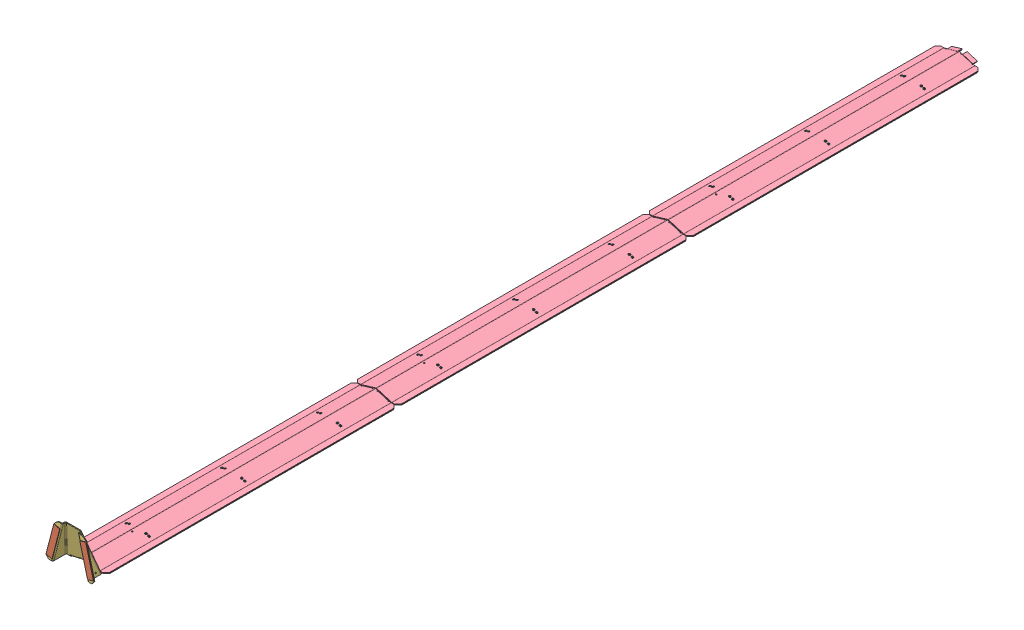
SolidWorks assembly GE-19227, configuration Default. Lengths in mm.
Overall size (196.8 153.5 3680.26).
68 component instances, 7 part files, 9 mates.
Components (placement in the parent):
- GE-19225-1: GE-19225 [Default] at (0 0 58.5238) size (196.8 153.5 83.53)
  - PEM-FH-832-6ZI-1: PEM-FH-832-6ZI [Default] at (71.1866 13.0582 -34.1814) x (-0.967724 -0.252012 0) z (-0.111181 0.426936 -0.897421) size (9.53 6.02 6.02)
  - Hook_1_5-1: Hook_1_5 [Default] at (-97.7586 14.7509 1.5875) x (0.252012 0.967724 0) z (-0.967724 0.252012 0) size (127 1.59 25.4)
  - Hook_1_5-2: Hook_1_5 [Default] at (65.7532 137.6519 1.5875) x (0.252012 -0.967724 0) z (0.967724 0.252012 0) size (127 1.59 25.4)
  - GE-19225-1-1: GE-19225-1 [Default] at origin size (196.8 153.5 81.94)
- GE-19226-1: GE-19226 [Default] at (0 1.5875 -609.5728) size (177.8 23.82 1219.2)
  - GE-19223-1: GE-19223 [Default] at origin size (177.8 22.23 1219.2)
    - GE-19223-1-1: GE-19223-1 [Default] at origin size (177.8 22.23 1219.2)
    - PEM-FH-832-6ZI-1: PEM-FH-832-6ZI [Default] at (7.1934 20.2237 419.1) x (-0.289806 -0.957086 0) z (-0.571052 0.172915 0.802496) size (9.53 6.02 6.02)
  - GE-19224-1: GE-19224 [Default] at (0.0601 3.1126 390.525) x (1 -0.000064 0) z (0 0 1) size (106.54 12.92 31.75)
  - GE-19224-2: GE-19224 [Default] at (0.0601 3.1126 -3.175) x (1 -0.000064 0) z (0 0 1) size (106.54 12.92 31.75)
  - GE-19224-3: GE-19224 [Default] at (0.0601 3.1126 -396.875) x (1 -0.000064 0) z (0 0 1) size (106.54 12.92 31.75)
  - rivet_.1563_.1875-.25-1: rivet_.1563_.1875-.25 [Default] at (47.0652 9.4775 390.525) x (-0.569603 0.172476 -0.80362) z (-0.289806 -0.957086 0) size (8.33 8.33 8.57)
  - rivet_.1563_.1875-.25-2: rivet_.1563_.1875-.25 [Default] at (-47.0652 9.4775 390.525) x (-0.904542 -0.273895 -0.326781) z (0.289806 -0.957086 0) size (8.33 8.33 8.57)
  - rivet_.1563_.1875-.25-3: rivet_.1563_.1875-.25 [Default] at (-34.9102 13.158 -3.175) x (-0.916013 -0.277369 0.289806) z (0.289806 -0.957086 0) size (8.33 8.33 8.57)
  - rivet_.1563_.1875-.25-4: rivet_.1563_.1875-.25 [Default] at (-47.0652 9.4775 -3.175) x (-0.916013 -0.277369 0.289806) z (0.289806 -0.957086 0) size (8.33 8.33 8.57)
  - rivet_.1563_.1875-.25-5: rivet_.1563_.1875-.25 [Default] at (34.9102 13.158 390.525) x (-0.284635 0.086188 0.954754) z (-0.289806 -0.957086 0) size (8.33 8.33 8.57)
  - rivet_.1563_.1875-.25-6: rivet_.1563_.1875-.25 [Default] at (-34.9102 13.158 390.525) x (-0.852981 -0.258283 0.453557) z (0.289806 -0.957086 0) size (8.33 8.33 8.57)
  - rivet_.1563_.1875-.25-7: rivet_.1563_.1875-.25 [Default] at (34.9102 13.158 -3.175) x (-0.728247 0.220513 -0.648868) z (-0.289806 -0.957086 0) size (8.33 8.33 8.57)
  - rivet_.1563_.1875-.25-9: rivet_.1563_.1875-.25 [Default] at (47.0652 9.4775 -3.175) x (-0.856065 0.259217 -0.447167) z (-0.289806 -0.957086 0) size (8.33 8.33 8.57)
  - rivet_.1563_.1875-.25-11: rivet_.1563_.1875-.25 [Default] at (47.0652 9.4775 -396.875) x (-0.934813 0.283061 -0.21448) z (-0.289806 -0.957086 0) size (8.33 8.33 8.57)
  - rivet_.1563_.1875-.25-13: rivet_.1563_.1875-.25 [Default] at (34.9102 13.158 -396.875) x (-0.956866 0.289739 0.021408) z (-0.289806 -0.957086 0) size (8.33 8.33 8.57)
  - rivet_.1563_.1875-.25-15: rivet_.1563_.1875-.25 [Default] at (-34.9102 13.158 -396.875) x (-0.945179 -0.2862 0.157243) z (0.289806 -0.957086 0) size (8.33 8.33 8.57)
  - rivet_.1563_.1875-.25-17: rivet_.1563_.1875-.25 [Default] at (-47.0652 9.4775 -396.875) x (-0.897265 -0.271692 0.347994) z (0.289806 -0.957086 0) size (8.33 8.33 8.57)
  - Hook_1_46-1: Hook_1_46 [Default] at (76.2 -1.5875 10.5486) x (0 0 -1) z (1 0 0) size (1168.4 1.59 25.4)
  - Hook_1_46-2: Hook_1_46 [Default] at (-76.2 -1.5875 10.5486) x (0 0 1) z (-1 0 0) size (1168.4 1.59 25.4)
- GE-19226-2: GE-19226 [Default] at (0 1.5875 -1810.0595) size (177.8 23.82 1219.2)
  - GE-19223-1: GE-19223 [Default] at origin size (177.8 22.23 1219.2)
    - GE-19223-1-1: GE-19223-1 [Default] at origin size (177.8 22.23 1219.2)
    - PEM-FH-832-6ZI-1: PEM-FH-832-6ZI [Default] at (7.1934 20.2237 419.1) x (-0.289806 -0.957086 0) z (-0.571052 0.172915 0.802496) size (9.53 6.02 6.02)
  - GE-19224-1: GE-19224 [Default] at (0.0601 3.1126 390.525) x (1 -0.000064 0) z (0 0 1) size (106.54 12.92 31.75)
  - GE-19224-2: GE-19224 [Default] at (0.0601 3.1126 -3.175) x (1 -0.000064 0) z (0 0 1) size (106.54 12.92 31.75)
  - GE-19224-3: GE-19224 [Default] at (0.0601 3.1126 -396.875) x (1 -0.000064 0) z (0 0 1) size (106.54 12.92 31.75)
  - rivet_.1563_.1875-.25-1: rivet_.1563_.1875-.25 [Default] at (47.0652 9.4775 390.525) x (-0.569603 0.172476 -0.80362) z (-0.289806 -0.957086 0) size (8.33 8.33 8.57)
  - rivet_.1563_.1875-.25-2: rivet_.1563_.1875-.25 [Default] at (-47.0652 9.4775 390.525) x (-0.904542 -0.273895 -0.326781) z (0.289806 -0.957086 0) size (8.33 8.33 8.57)
  - rivet_.1563_.1875-.25-3: rivet_.1563_.1875-.25 [Default] at (-34.9102 13.158 -3.175) x (-0.916013 -0.277369 0.289806) z (0.289806 -0.957086 0) size (8.33 8.33 8.57)
  - rivet_.1563_.1875-.25-4: rivet_.1563_.1875-.25 [Default] at (-47.0652 9.4775 -3.175) x (-0.916013 -0.277369 0.289806) z (0.289806 -0.957086 0) size (8.33 8.33 8.57)
  - rivet_.1563_.1875-.25-5: rivet_.1563_.1875-.25 [Default] at (34.9102 13.158 390.525) x (-0.284635 0.086188 0.954754) z (-0.289806 -0.957086 0) size (8.33 8.33 8.57)
  - rivet_.1563_.1875-.25-6: rivet_.1563_.1875-.25 [Default] at (-34.9102 13.158 390.525) x (-0.852981 -0.258283 0.453557) z (0.289806 -0.957086 0) size (8.33 8.33 8.57)
  - rivet_.1563_.1875-.25-7: rivet_.1563_.1875-.25 [Default] at (34.9102 13.158 -3.175) x (-0.728247 0.220513 -0.648868) z (-0.289806 -0.957086 0) size (8.33 8.33 8.57)
  - rivet_.1563_.1875-.25-9: rivet_.1563_.1875-.25 [Default] at (47.0652 9.4775 -3.175) x (-0.856065 0.259217 -0.447167) z (-0.289806 -0.957086 0) size (8.33 8.33 8.57)
  - rivet_.1563_.1875-.25-11: rivet_.1563_.1875-.25 [Default] at (47.0652 9.4775 -396.875) x (-0.934813 0.283061 -0.21448) z (-0.289806 -0.957086 0) size (8.33 8.33 8.57)
  - rivet_.1563_.1875-.25-13: rivet_.1563_.1875-.25 [Default] at (34.9102 13.158 -396.875) x (-0.956866 0.289739 0.021408) z (-0.289806 -0.957086 0) size (8.33 8.33 8.57)
  - rivet_.1563_.1875-.25-15: rivet_.1563_.1875-.25 [Default] at (-34.9102 13.158 -396.875) x (-0.945179 -0.2862 0.157243) z (0.289806 -0.957086 0) size (8.33 8.33 8.57)
  - rivet_.1563_.1875-.25-17: rivet_.1563_.1875-.25 [Default] at (-47.0652 9.4775 -396.875) x (-0.897265 -0.271692 0.347994) z (0.289806 -0.957086 0) size (8.33 8.33 8.57)
  - Hook_1_46-1: Hook_1_46 [Default] at (76.2 -1.5875 10.5486) x (0 0 -1) z (1 0 0) size (1168.4 1.59 25.4)
  - Hook_1_46-2: Hook_1_46 [Default] at (-76.2 -1.5875 10.5486) x (0 0 1) z (-1 0 0) size (1168.4 1.59 25.4)
- GE-19226-3: GE-19226 [Default] at (0 1.5875 -3010.5462) size (177.8 23.82 1219.2)
  - GE-19223-1: GE-19223 [Default] at origin size (177.8 22.23 1219.2)
    - GE-19223-1-1: GE-19223-1 [Default] at origin size (177.8 22.23 1219.2)
    - PEM-FH-832-6ZI-1: PEM-FH-832-6ZI [Default] at (7.1934 20.2237 419.1) x (-0.289806 -0.957086 0) z (-0.571052 0.172915 0.802496) size (9.53 6.02 6.02)
  - GE-19224-1: GE-19224 [Default] at (0.0601 3.1126 390.525) x (1 -0.000064 0) z (0 0 1) size (106.54 12.92 31.75)
  - GE-19224-2: GE-19224 [Default] at (0.0601 3.1126 -3.175) x (1 -0.000064 0) z (0 0 1) size (106.54 12.92 31.75)
  - GE-19224-3: GE-19224 [Default] at (0.0601 3.1126 -396.875) x (1 -0.000064 0) z (0 0 1) size (106.54 12.92 31.75)
  - rivet_.1563_.1875-.25-1: rivet_.1563_.1875-.25 [Default] at (47.0652 9.4775 390.525) x (-0.569603 0.172476 -0.80362) z (-0.289806 -0.957086 0) size (8.33 8.33 8.57)
  - rivet_.1563_.1875-.25-2: rivet_.1563_.1875-.25 [Default] at (-47.0652 9.4775 390.525) x (-0.904542 -0.273895 -0.326781) z (0.289806 -0.957086 0) size (8.33 8.33 8.57)
  - rivet_.1563_.1875-.25-3: rivet_.1563_.1875-.25 [Default] at (-34.9102 13.158 -3.175) x (-0.916013 -0.277369 0.289806) z (0.289806 -0.957086 0) size (8.33 8.33 8.57)
  - rivet_.1563_.1875-.25-4: rivet_.1563_.1875-.25 [Default] at (-47.0652 9.4775 -3.175) x (-0.916013 -0.277369 0.289806) z (0.289806 -0.957086 0) size (8.33 8.33 8.57)
  - rivet_.1563_.1875-.25-5: rivet_.1563_.1875-.25 [Default] at (34.9102 13.158 390.525) x (-0.284635 0.086188 0.954754) z (-0.289806 -0.957086 0) size (8.33 8.33 8.57)
  - rivet_.1563_.1875-.25-6: rivet_.1563_.1875-.25 [Default] at (-34.9102 13.158 390.525) x (-0.852981 -0.258283 0.453557) z (0.289806 -0.957086 0) size (8.33 8.33 8.57)
  - rivet_.1563_.1875-.25-7: rivet_.1563_.1875-.25 [Default] at (34.9102 13.158 -3.175) x (-0.728247 0.220513 -0.648868) z (-0.289806 -0.957086 0) size (8.33 8.33 8.57)
  - rivet_.1563_.1875-.25-9: rivet_.1563_.1875-.25 [Default] at (47.0652 9.4775 -3.175) x (-0.856065 0.259217 -0.447167) z (-0.289806 -0.957086 0) size (8.33 8.33 8.57)
  - rivet_.1563_.1875-.25-11: rivet_.1563_.1875-.25 [Default] at (47.0652 9.4775 -396.875) x (-0.934813 0.283061 -0.21448) z (-0.289806 -0.957086 0) size (8.33 8.33 8.57)
  - rivet_.1563_.1875-.25-13: rivet_.1563_.1875-.25 [Default] at (34.9102 13.158 -396.875) x (-0.956866 0.289739 0.021408) z (-0.289806 -0.957086 0) size (8.33 8.33 8.57)
  - rivet_.1563_.1875-.25-15: rivet_.1563_.1875-.25 [Default] at (-34.9102 13.158 -396.875) x (-0.945179 -0.2862 0.157243) z (0.289806 -0.957086 0) size (8.33 8.33 8.57)
  - rivet_.1563_.1875-.25-17: rivet_.1563_.1875-.25 [Default] at (-47.0652 9.4775 -396.875) x (-0.897265 -0.271692 0.347994) z (0.289806 -0.957086 0) size (8.33 8.33 8.57)
  - Hook_1_46-1: Hook_1_46 [Default] at (76.2 -1.5875 10.5486) x (0 0 -1) z (1 0 0) size (1168.4 1.59 25.4)
  - Hook_1_46-2: Hook_1_46 [Default] at (-76.2 -1.5875 10.5486) x (0 0 1) z (-1 0 0) size (1168.4 1.59 25.4)
Mates (geometry in assembly coordinates):
- Coincident5: coincident: plane of GE-19225-1/GE-19225-1-1 through (0 0 58.5238) normal (1 0 0); plane of ? through (0 -1.5875 609.6272) normal (1 0 0)
- Coincident7: coincident: unknown of ?; unknown of ?
- Coincident8: coincident: plane of ? through (-88.9 -1.5875 0.0272) normal (-1 0 0); plane of ? through (-88.9 -1.5875 1200.5138) normal (-1 0 0)
- Coincident9: coincident: line of ? through (10.2065 -17.5815 1200.5138) axis (0.957086 0.289806 0); line of ? through (64.2319 -4.6253 1200.5138) axis (0 0 -1)
- Coincident10: coincident: plane of ? through (-63.5 -1.5875 1200.5138) normal (0 1 0); plane of ? through (-63.5 -1.5875 2401.0005) normal (0 1 0)
- Coincident11: coincident: plane of ? through (-88.9 -1.5875 1200.5138) normal (-1 0 0); plane of ? through (-88.9 -1.5875 2401.0005) normal (-1 0 0)
- Coincident12: coincident: line of ? through (-52.749 -4.6996 2401.0005) axis (0.957086 -0.289806 0); plane of ? through (1.1159 -23.6514 2401.0005) normal (0 0 -1)
- Coincident15: coincident: plane of GE-19225-1/GE-19225-1-1 through (0 0 58.5238) normal (0 1 0); plane of GE-19226-1/Hook_1_46-1 through (76.2 0 -599.0242) normal (0 -1 0)
- Coincident17: coincident: line of GE-19225-1/GE-19225-1-1 through (15.875 50.8 0.8252) axis (0.000027 1 0); line of ? through (64.2319 -4.6253 0.0272) axis (0 0 -1)
